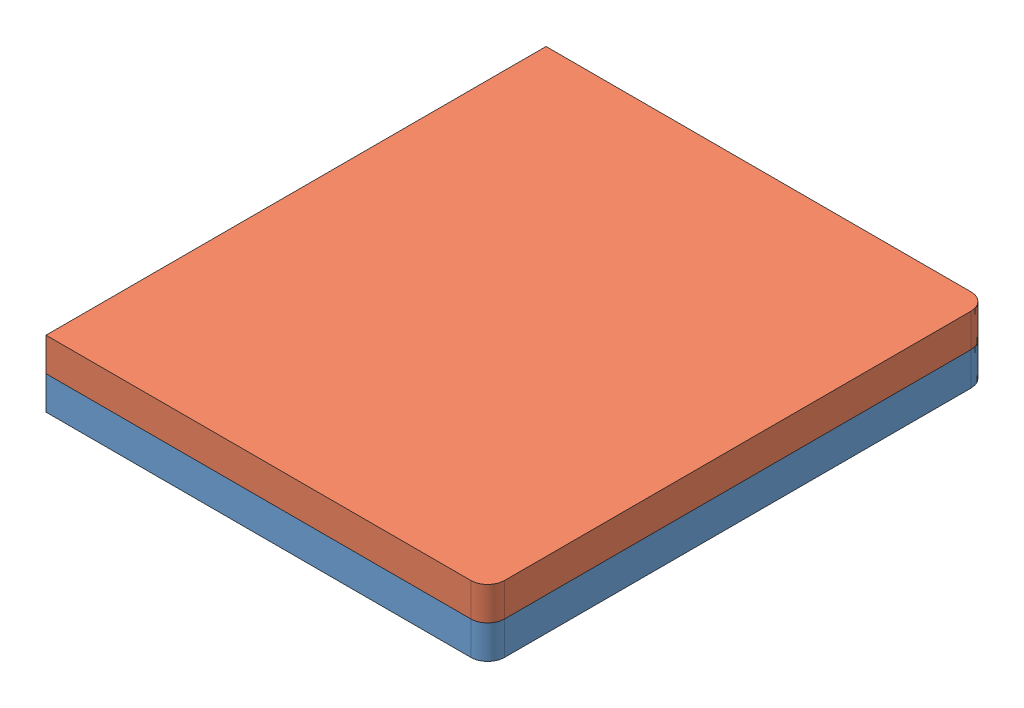
SolidWorks assembly 装配体3, configuration Default. Lengths in mm.
Overall size (107.5 16 120).
2 component instances, 2 part files, 3 mates.
Components (placement in the parent):
- 充电座V1.0-底座-右-1: 充电座V1.0-底座-右 [Default] at (110.8398 61.3889 88.6295) size (107.5 9.5 120)
- 充电座V1.0-底座-左-1: 充电座V1.0-底座-左 [Default] at (110.8398 61.3889 88.6295) x (1 0 0) z (0 0 -1) size (107.5 9.5 120)
Mates (geometry in assembly coordinates):
- 重合7: coincident anti-aligned: circle of 充电座V1.0-底座-右-1; circle of 充电座V1.0-底座-左-1
- LimitAngle2: limit planar angle = 0 rad anti-aligned: line of 充电座V1.0-底座-右-1 through (4.8398 61.3889 148.6295) axis (1 0 0); line of 充电座V1.0-底座-左-1 through (106.8398 61.3889 148.6295) axis (-1 0 0)
- 重合9: coincident aligned: circle of 充电座V1.0-底座-右-1; circle of ?
